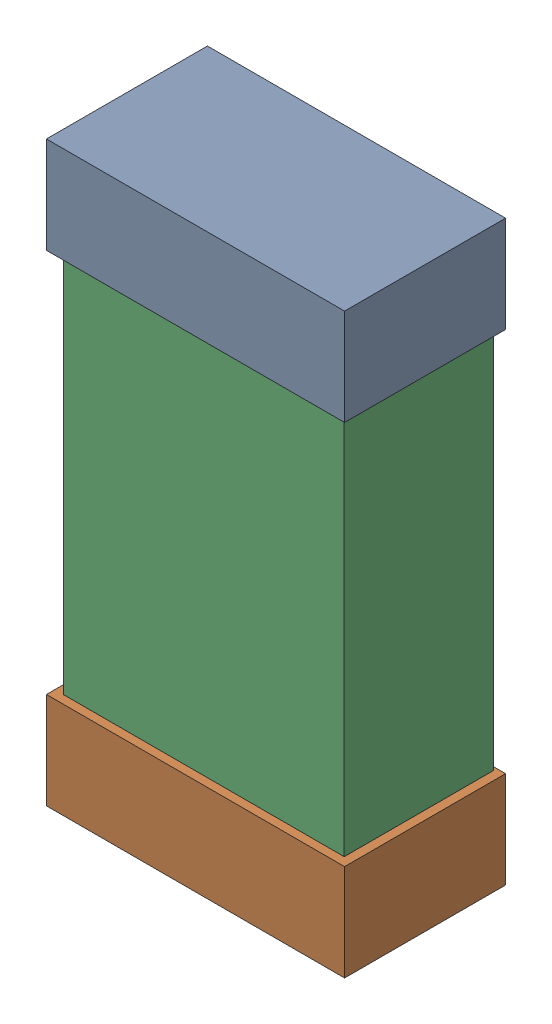
SolidWorks assembly C37, configuration Default. Lengths in mm.
Overall size (0.85 1.65 0.46).
6 component instances, 2 part files, 0 mates.
Components (placement in the parent):
- 432138512_48-1: 432138512_48 [Default] at (15.4501 50.8362 -0.8715) size (0.85 0.28 0.46)
  - Extruded-1: Extruded [Default] at origin size (0.85 0.28 0.46)
- 432138512_49-1: 432138512_49 [Default] at (15.4501 49.4647 -0.8715) size (0.85 0.28 0.46)
  - Extruded-1: Extruded [Default] at origin size (0.85 0.28 0.46)
- 432124816_24-1: 432124816_24 [Default] at (15.4501 50.1505 -0.8615) size (0.8 1.5 0.42)
  - Extruded (1)-1: Extruded (1) [Default] at origin size (0.8 1.5 0.42)
